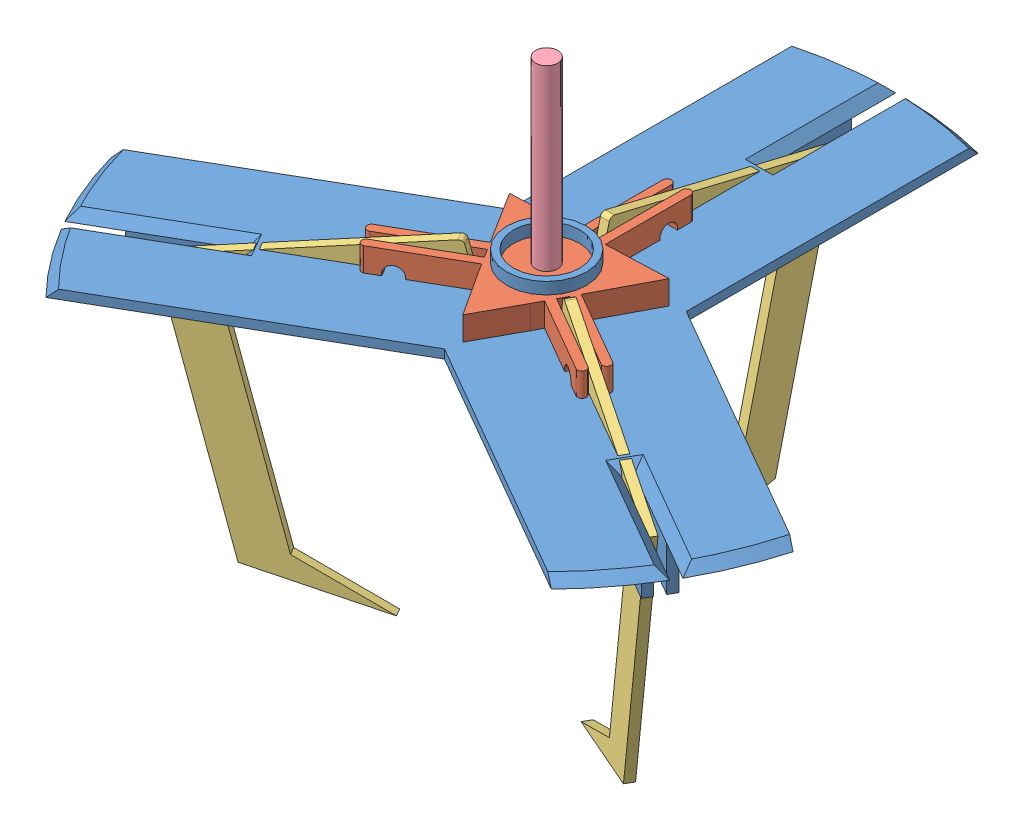
SolidWorks assembly gripping arm, configuration Default. Lengths in mm.
Overall size (154.16 385.24 139.46).
6 component instances, 4 part files, 7 mates.
Components (placement in the parent):
- holder-1: holder [Default] at (57.5052 102.868 110.8238) size (154.16 20 136.04)
- pneumatic to arm-1: pneumatic to arm [Default] at (57.5052 110.2133 110.8238) x (0.999262 0 -0.038423) z (-0.038423 0 -0.999262) size (54.95 10 50.14)
- finger1-1: finger1 [Default] at (57.175 67.9824 112.2847) x (-0.841925 -0.23427 0.486086) z (0.202884 -0.972172 -0.117135) size (52.65 2 70.98)
- rod-1: rod [Default] at (57.5052 100.4837 110.8238) x (0.882577 0 0.470169) z (-0.470169 0 0.882577) size (5 50 5)
- finger1-2: finger1 [Default] at (56.4052 67.9824 109.8074) x (0 -0.23427 -0.972172) z (0 -0.972172 0.23427) size (52.65 2 70.98)
- finger1-3: finger1 [Default] at (58.9355 67.9824 110.3794) x (0.841925 -0.23427 0.486086) z (-0.202884 -0.972172 -0.117135) size (52.65 2 70.98)
Mates (geometry in assembly coordinates):
- Parallel2: parallel: plane of holder-1 through (60.6052 92.868 60.8238) normal (1 0 0); plane of pneumatic to arm-1
- Concentric6: concentric aligned: circle of holder-1; circle of rod-1
- Concentric7: concentric anti-aligned: circle of holder-1; circle of pneumatic to arm-1
- Parallel7: parallel aligned: plane of holder-1 through (99.2565 92.868 138.5085) normal (-0.5 0 0.866025); plane of pneumatic to arm-1 through (64.2154 100.2133 118.2382) normal (-0.5 0 0.866025)
- Lock2: lock: unknown of pneumatic to arm-1; unknown of rod-1
- Coincident11: coincident anti-aligned: circle of holder-1; circle of finger1-1
- Tangent2: tangent anti-aligned: cylinder of pneumatic to arm-1 through (39.7387 105.2133 129.0881) axis (-0.5 0 -0.866025) radius 2; plane of finger1-1 through (34.6799 106.9529 122.9628) normal (0.202884 -0.972172 -0.117135)
